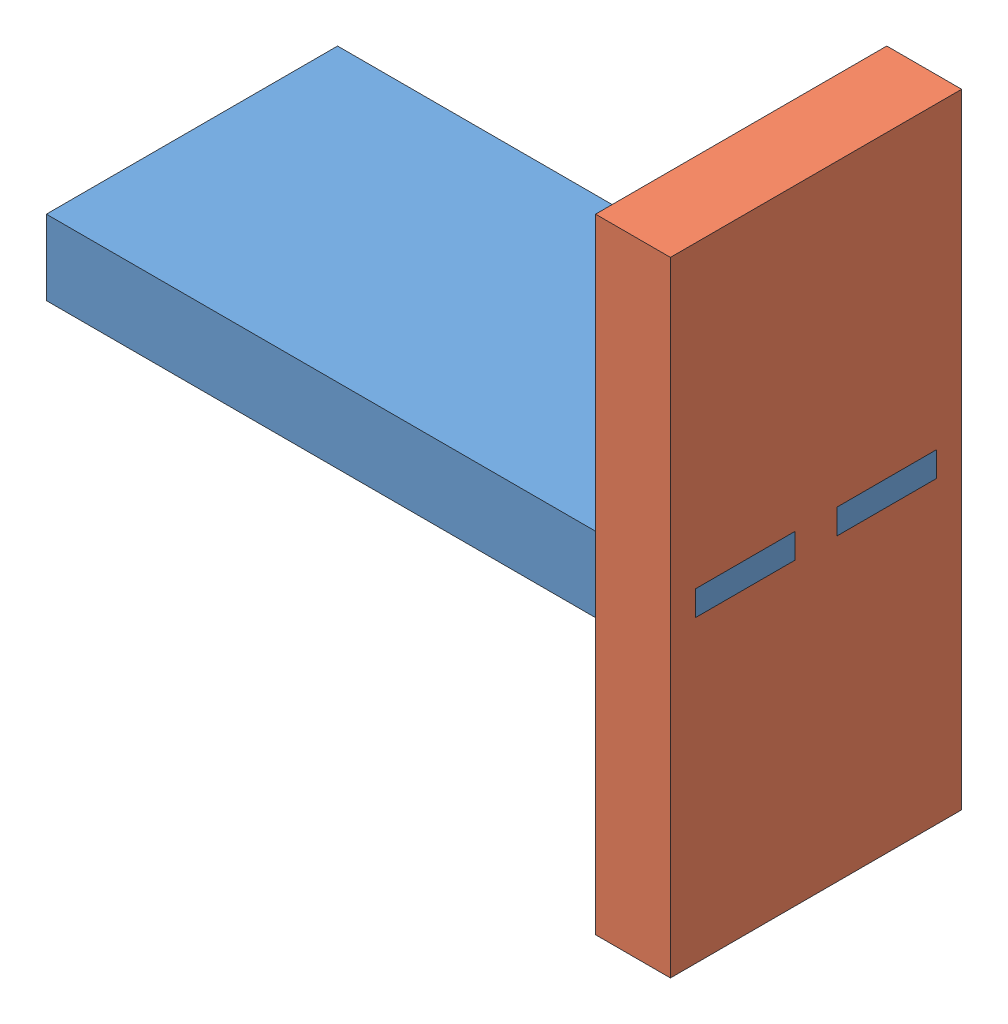
SolidWorks assembly Assem 1, configuration Default. Lengths in mm.
Overall size (150 150 70).
2 component instances, 2 part files, 6 mates.
Components (placement in the parent):
- Part 1-1: Part 1 [Default] at (-24.5458 84 -70) x (0 0 1) z (0 1 0) size (70 150 18)
- Part 2-1: Part 2 [Default] at (107.4542 0 -70) x (0 0 1) z (-1 0 0) size (70 150 18)
Mates (geometry in assembly coordinates):
- Coincident1: coincident: plane of ? through (108.1234 0 -70) normal (0 -1 0)
- Coincident2: coincident aligned: plane of ? through (108.1234 150 0) normal (0 0 1)
- Coincident3: coincident: plane of Part 1-1 through (107.4542 84 0) normal (0 0 1); plane of Part 2-1 through (107.4542 150 0) normal (0 0 1)
- Coincident4: coincident: plane of Part 1-1 through (125.4542 72 -6) normal (0 0 1); plane of Part 2-1 through (125.4542 72 -6) normal (0 0 -1)
- Coincident5: coincident: plane of Part 1-1 through (125.4542 84 -70) normal (1 0 0); plane of Part 2-1 through (125.4542 150 -70) normal (1 0 0)
- Coincident6: coincident anti-aligned: plane of Part 1-1 through (125.4542 78 -6) normal (0 1 0); plane of Part 2-1 through (125.4542 78 -6) normal (0 -1 0)
